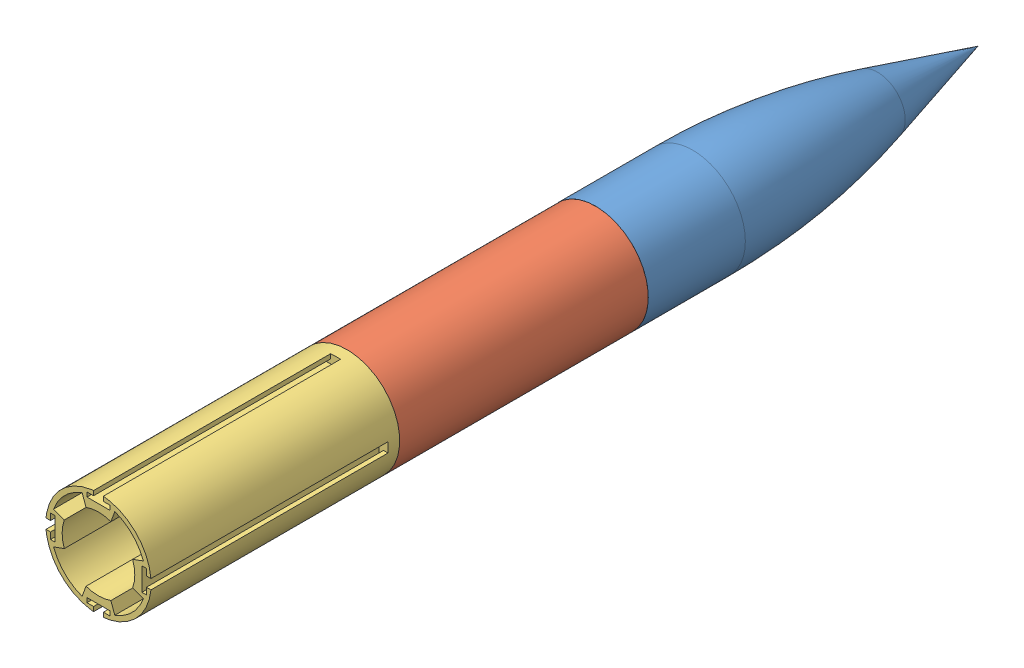
SolidWorks assembly Assem1, configuration Default. Lengths in mm.
Overall size (49.16 49.16 292.1).
4 component instances, 4 part files, 6 mates.
Components (placement in the parent):
- nose-1: nose [Default] at (-6.9082 6.6775 62.6088) size (35 35 127)
- body-1: body [Default] at (-6.9082 6.6775 145.1588) x (0.619361 0.785106 0) z (0 0 1) size (35 35 101.6)
- tail_main_rev3-1: tail_main_rev3 [Default] at (-6.9082 6.6775 227.7088) size (35 35 101.6)
- engine_stop-1: engine_stop [Default] at (-6.9082 6.6775 158.1945) x (0.013342 0.999911 0) z (0 0 -1) size (28.97 28.97 4.32)
Mates (geometry in assembly coordinates):
- Concentric1: concentric anti-aligned: cylinder of nose-1 through (-6.9082 6.6775 37.2088) axis (0 0 1) radius 15.113; cylinder of body-1 through (-6.9082 6.6775 43.5588) axis (0 0 -1) radius 15
- Coincident1: coincident anti-aligned: plane of nose-1 through (-6.9082 6.6775 62.6088) normal (0 0 1); plane of body-1 through (-16.1986 -5.0991 62.6088) normal (0 0 -1)
- Concentric2: concentric anti-aligned: cylinder of body-1 through (-6.9082 6.6775 72.0068) axis (0 0 1) radius 15.113; cylinder of tail_main_rev3-1 through (-6.9082 6.6775 126.1088) axis (0 0 -1) radius 15
- Coincident2: coincident anti-aligned: plane of body-1 through (-6.9082 6.6775 145.1588) normal (0 0 1); plane of tail_main_rev3-1 through (-21.9082 6.6775 145.1588) normal (0 0 -1)
- Concentric3: concentric anti-aligned: cylinder of tail_main_rev3-1 through (-6.9082 6.6775 126.1088) axis (0 0 1) radius 12.065; cylinder of engine_stop-1 through (-6.9082 6.6775 158.1945) axis (0 0 -1) radius 10.1494
- Coincident3: coincident aligned: cone of tail_main_rev3-1 through (-6.9082 6.6775 159.1288) axis (0 0 -1); cone of engine_stop-1 through (-6.9082 6.6775 153.8765) axis (0 0 -1)
